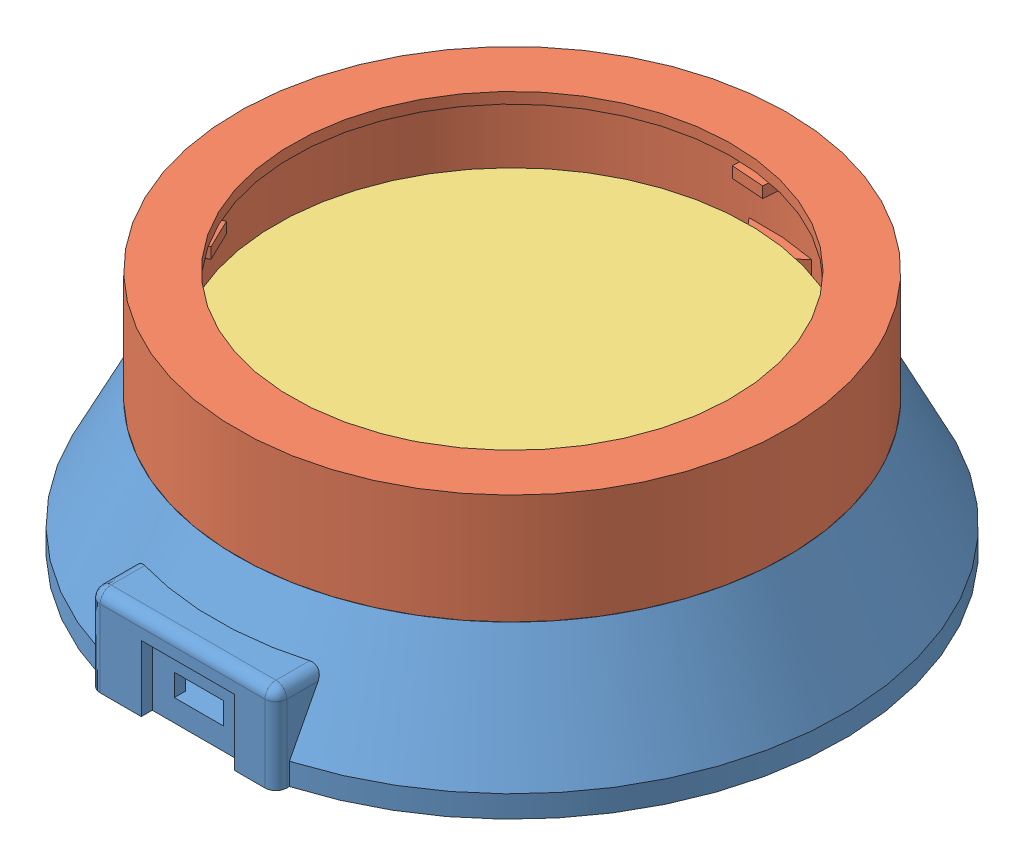
SolidWorks assembly 投影灯, configuration 默认. Lengths in mm.
Overall size (133.56 44.01 133.56).
3 component instances, 3 part files, 4 mates.
Components (placement in the parent):
- 投影灯下部-2: 投影灯下部 [默认] at (-0.3826 -21.6285 120) size (120 28 120)
- 投影灯上部-2: 投影灯上部 [默认] at (-0.3826 22.3783 120) x (0.435268 0 0.900301) z (0.900301 0 -0.435268) size (100 27.4 100)
- 灯板^投影灯-1: 灯板^投影灯 [默认] at (-0.3826 6.4222 120) x (-0.505312 0 -0.862937) z (0.862937 0 -0.505312) size (86 1.8 86) (virtual)
Mates (geometry in assembly coordinates):
- 平行3: parallel anti-aligned: plane of 投影灯下部-2 through (-0.3826 2.3715 120) normal (0 1 0); plane of 投影灯上部-2 through (-0.3826 2.3783 120) normal (0 -1 0)
- 同心1: concentric anti-aligned: circle of 投影灯下部-2; circle of 投影灯上部-2
- 同心4: concentric anti-aligned: cylinder of 投影灯上部-2 through (-0.3826 20.3783 120) axis (0 1 0) radius 50; cylinder of 灯板^投影灯-1 through (-0.3826 8.2222 120) axis (0 -1 0) radius 43
- 锁定1: lock: unknown of 投影灯上部-2; unknown of 灯板^投影灯-1
